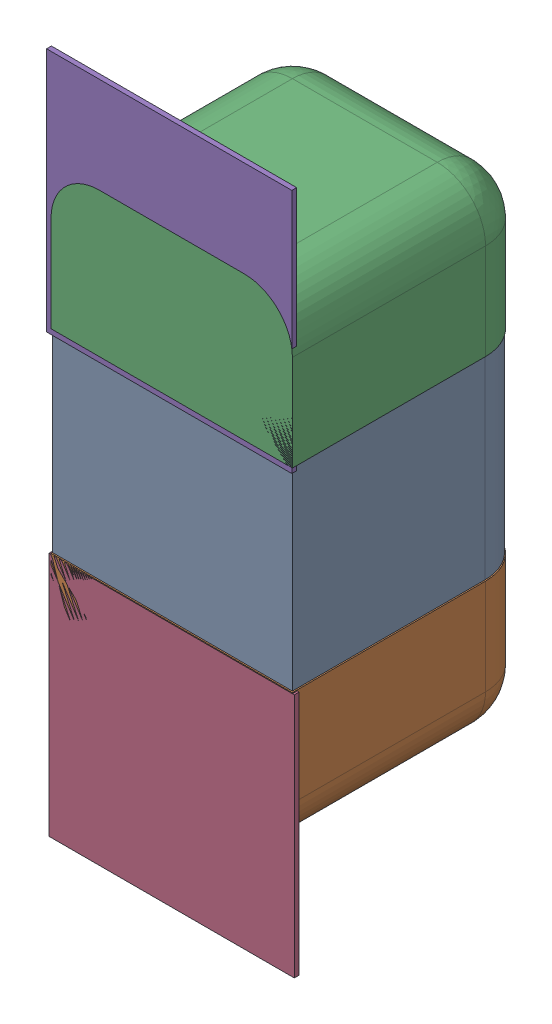
SolidWorks assembly C104, configuration Défaut. Lengths in mm.
Overall size (0.51 1.41 0.5).
8 component instances, 4 part files, 0 mates.
Components (placement in the parent):
- 6501210464-1: 6501210464 [Défaut] at (10.8966 -9.106 -2.0818) x (0 1 0) z (-1 0 0) size (1 0.5 0.5)
  - Open CASCADE STEP translator 7.5 2.33.1.1-1: Open CASCADE STEP translator 7.5 2.33.1.1 [Défaut] at origin size (0.4 0.5 0.5)
  - Open CASCADE STEP translator 7.5 2.33.1.2-1: Open CASCADE STEP translator 7.5 2.33.1.2 [Défaut] at origin size (0.3 0.5 0.5)
  - Open CASCADE STEP translator 7.5 2.33.1.3-1: Open CASCADE STEP translator 7.5 2.33.1.3 [Défaut] at origin size (0.3 0.5 0.5)
- 6504207776-1: 6504207776 [Défaut] at (10.8966 -9.5633 -2.0918) size (0.51 0.51 0.01)
  - Extruded-1: Extruded [Défaut] at origin size (0.51 0.51 0.01)
- 6504207776-2: 6504207776 [Défaut] at (10.8914 -8.661 -2.0918) size (0.51 0.51 0.01)
  - Extruded-1: Extruded [Défaut] at origin size (0.51 0.51 0.01)
